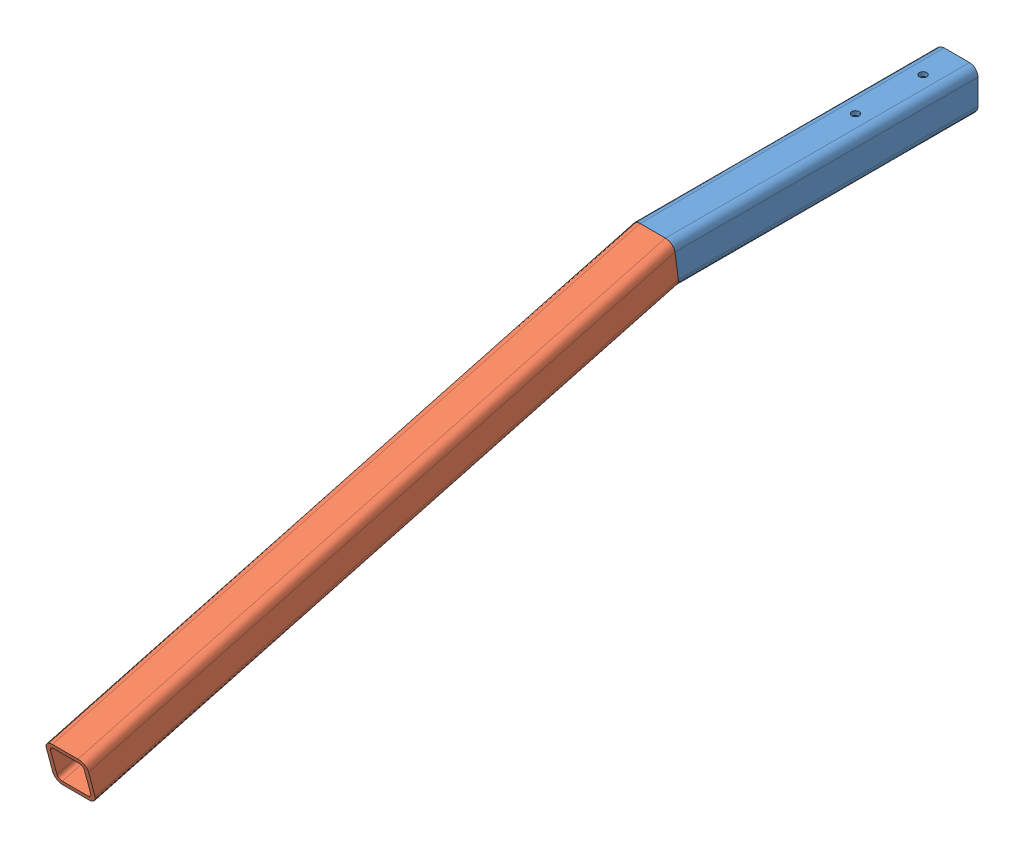
SolidWorks assembly Leg Assy, configuration Default. Lengths in mm.
Overall size (63.5 298 1340.44).
2 component instances, 2 part files, 6 mates.
Components (placement in the parent):
- leg pt 1-1: leg pt 1 [Default] at (0 12.4774 0) size (63.5 63.5 457.2)
- leg pt 2-1: leg pt 2 [Default] at (0 -104.7728 662.0038) x (1 0 0) z (0 -0.258819 0.965926) size (63.5 63.5 914.4)
Mates (geometry in assembly coordinates):
- Coincident1: coincident aligned: plane of leg pt 1-1 through (0 12.4774 0) normal (0 0 1); plane of assembly through (0 0 0) normal (0 0 1)
- Coincident2: coincident aligned: plane of leg pt 1-1 through (0 12.4774 0) normal (1 0 0); plane of assembly through (0 0 0) normal (1 0 0)
- Coincident3: coincident aligned: plane of leg pt 1-1 through (0 12.4774 0) normal (0 0 1); plane of assembly through (0 0 0) normal (0 0 1)
- Coincident4: coincident anti-aligned: plane of leg pt 1-1 through (-31.75 -67.1658 213.9348) normal (0 -0.130526 0.991445); plane of leg pt 2-1 through (-882.65 59.2288 230.575) normal (0 0.130526 -0.991445)
- Coincident5: coincident aligned: plane of leg pt 1-1 through (0 12.4774 0) normal (1 0 0); plane of leg pt 2-1
- Coincident6: coincident aligned: line of leg pt 1-1 through (19.05 44.2274 228.6) axis (-1 0 0); line of leg pt 2-1 through (19.05 44.2274 228.6) axis (-1 0 0)
